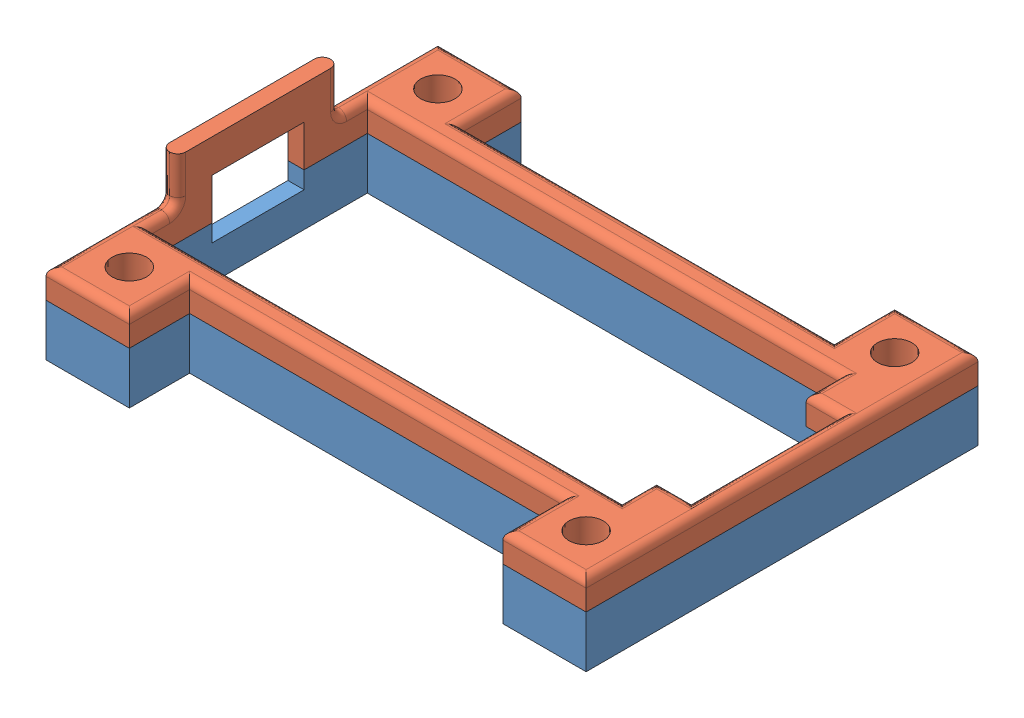
SolidWorks assembly ArduinoNanoBox, configuration Default. Lengths in mm.
Overall size (47 11 34.1).
2 component instances, 2 part files, 3 mates.
Components (placement in the parent):
- ArduinoBoxBottomV2-1: ArduinoBoxBottomV2 [Default] at (-4.4979 28.1002 45.2802) size (47 4.5 34.1)
- ArduinoBoxTopV2-1: ArduinoBoxTopV2 [Default] at (-4.4979 29.6002 45.2802) size (47 6.5 34.1)
Mates (geometry in assembly coordinates):
- Coincident1: coincident anti-aligned: plane of ArduinoBoxBottomV2-1 through (-4.4979 32.6002 45.2802) normal (0 1 0); plane of ArduinoBoxTopV2-1 through (-4.4979 32.6002 45.2802) normal (0 -1 0)
- Coincident2: coincident aligned: plane of ArduinoBoxBottomV2-1 through (-5.9079 32.6002 23.9802) normal (0 0 -1); plane of ArduinoBoxTopV2-1 through (-5.9079 35.1002 23.9802) normal (0 0 -1)
- Coincident3: coincident aligned: plane of ArduinoBoxBottomV2-1 through (41.0921 32.6002 23.9802) normal (1 0 0); plane of ArduinoBoxTopV2-1 through (41.0921 35.1002 23.9802) normal (1 0 0)
